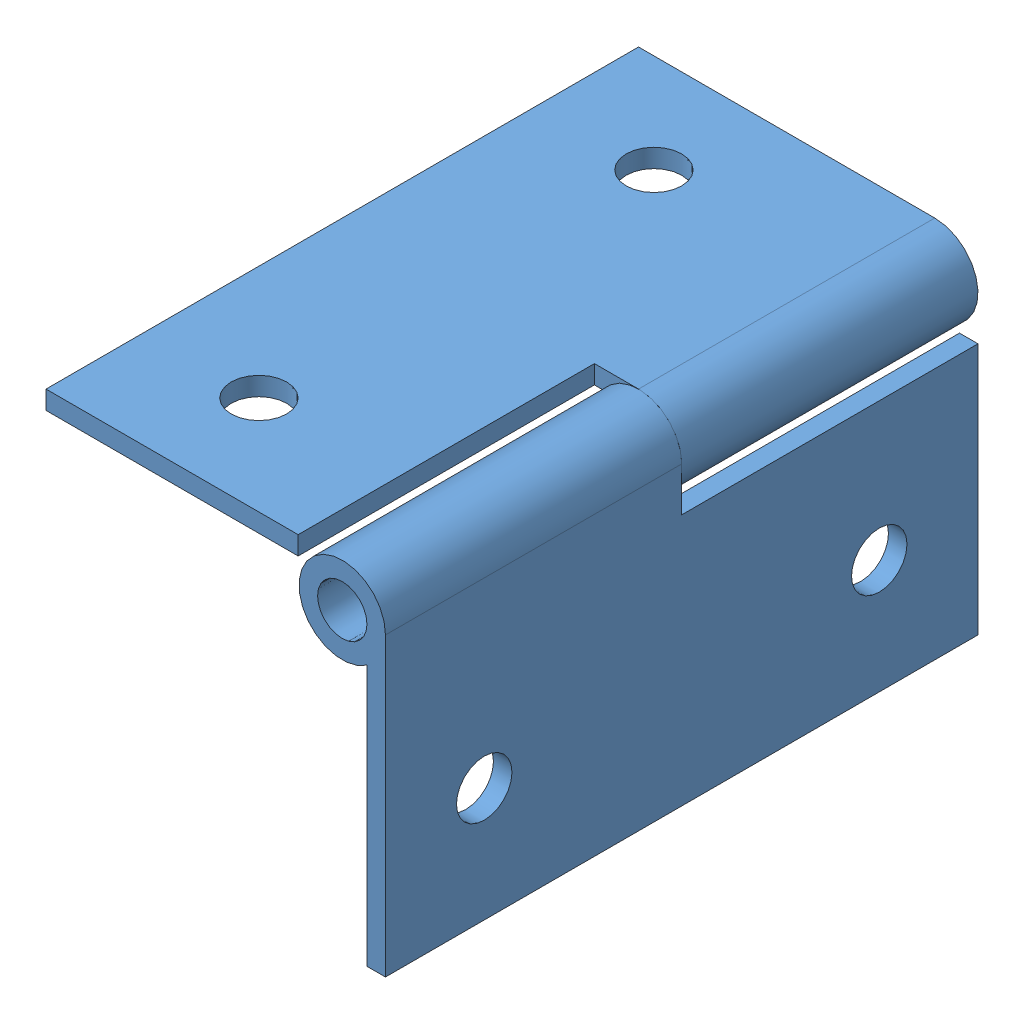
SolidWorks assembly 181226_Hinge_1, configuration Default. Lengths in mm.
Overall size (43.66 43.66 76.2).
2 component instances, 1 part files, 3 mates.
Components (placement in the parent):
- 181226_Hinge_1_Half-1: 181226_Hinge_1_Half [Default] at origin size (11.11 43.66 76.2)
- 181226_Hinge_1_Half-2: 181226_Hinge_1_Half [Default] at (114.2265 -114.2265 0) x (0 1 0) z (0 0 -1) size (11.11 43.66 76.2)
Mates (geometry in assembly coordinates):
- Coincident1: coincident anti-aligned: plane of 181226_Hinge_1_Half-1 through (208.7282 94.5017 0) normal (0 0 -1); plane of 181226_Hinge_1_Half-2 through (208.7282 94.5017 0) normal (0 0 1)
- Concentric1: concentric anti-aligned: circle of 181226_Hinge_1_Half-1; circle of 181226_Hinge_1_Half-2
- Perpendicular1: perpendicular: plane of 181226_Hinge_1_Half-1 through (211.904 56.4017 38.1) normal (-1 0 0); plane of 181226_Hinge_1_Half-2 through (170.6282 97.6775 -38.1) normal (0 -1 0)
